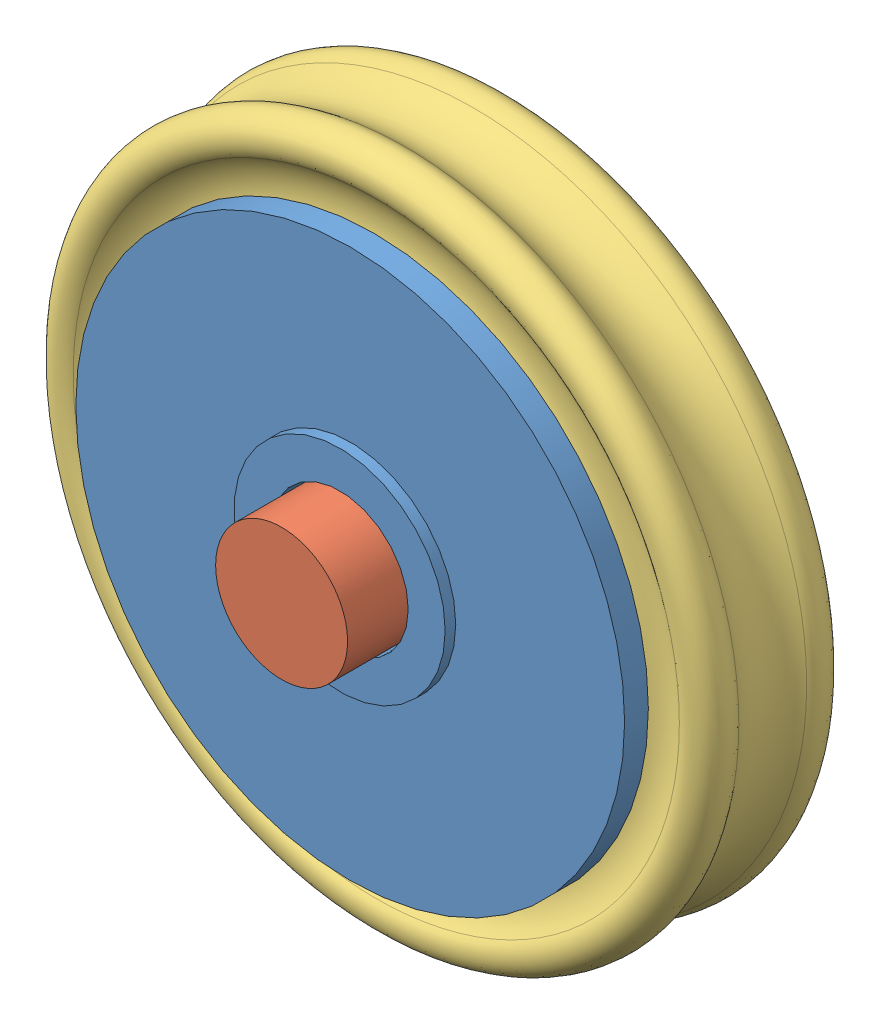
SolidWorks assembly wheel_roller_asm, configuration Default. Lengths in mm.
Overall size (12.8 12.8 6).
3 component instances, 3 part files, 3 mates.
Components (placement in the parent):
- wheel_roller_hub-1: wheel_roller_hub [Default] at (-28.6925 -1.096 17.7852) size (10.4 10.4 3.8)
- wheel_roller_pin-1: wheel_roller_pin [Default] at (-28.6925 -1.096 14.7852) size (2.5 2.5 6)
- xring_109-1: xring_109 [Default] at (-28.6925 -1.096 17.7852) size (12.8 12.8 2.6)
Mates (geometry in assembly coordinates):
- Concentric1: concentric anti-aligned: cylinder of wheel_roller_hub-1 through (-28.6925 -1.096 19.6852) axis (0 0 1) radius 1.3; cylinder of wheel_roller_pin-1 through (-28.6925 -1.096 20.7852) axis (0 0 -1) radius 1.25
- Width1: width aligned: plane of wheel_roller_hub-1 through (-28.6925 0.204 19.6852) normal (0 0 1); plane of wheel_roller_hub-1 through (-28.6925 0.904 15.8852) normal (0 0 -1); plane of wheel_roller_pin-1 through (-28.6925 -1.096 20.7852) normal (0 0 1); plane of wheel_roller_pin-1 through (-28.6925 -1.096 14.7852) normal (0 0 -1)
- Coincident1: coordinate: point of wheel_roller_hub-1; point of xring_109-1
